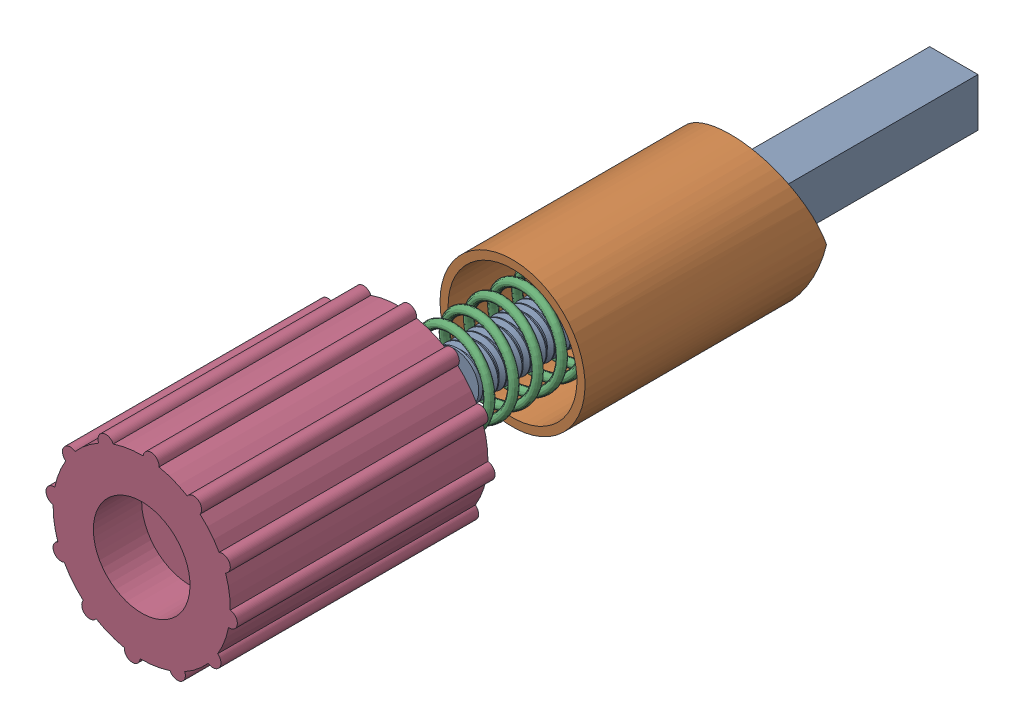
SolidWorks assembly tensioner, configuration Default. Lengths in mm.
Overall size (27.98 27.98 100.86).
4 component instances, 4 part files, 5 mates.
Components (placement in the parent):
- rod-1: rod [Default] at (10.8245 13.8534 -15.1237) size (6 6 62)
- p2[1]-1: p2[1] [Default] at (10.8245 13.8534 39.6825) x (0.011455 -0.999934 0) z (0.999934 0.011455 0) size (18 30 18)
- Spring-1: Spring [Default] at (10.8245 13.8534 65.8293) x (0.969373 0.245591 0) z (-0.245591 0.969373 0) size (11.45 51.99 11.45)
- p11-1: p11 [Default] at (10.8245 13.8534 53.7332) x (-0.195144 -0.980775 0) z (0 0 1) size (23.8 23.8 32)
Mates (geometry in assembly coordinates):
- Concentric2: concentric anti-aligned: cylinder of rod-1 through (10.8245 13.8534 26.8763) axis (0 0 -1) radius 3; cylinder of p2[1]-1 through (10.8245 13.8534 12.6825) axis (0 0 1) radius 8
- Concentric3: concentric aligned: cylinder of p2[1]-1 through (10.8245 13.8534 12.6825) axis (0 0 1) radius 8; cylinder of p11-1 through (10.8245 13.8534 79.7332) axis (0 0 1) radius 6
- Coincident3: coincident anti-aligned: line of rod-1 through (10.8245 13.8534 48.1757) axis (0 0 -1); line of Spring-1 through (10.8245 13.8534 12.6825) axis (0 0 1)
- Coincident4: coincident: plane of assembly; point of Spring-1; plane of p11-1 through (10.8245 13.8534 68.7332) normal (0 0 -1)
- Coincident5: coincident: plane of p2[1]-1 through (10.8245 13.8534 12.6825) normal (0 0 1)
